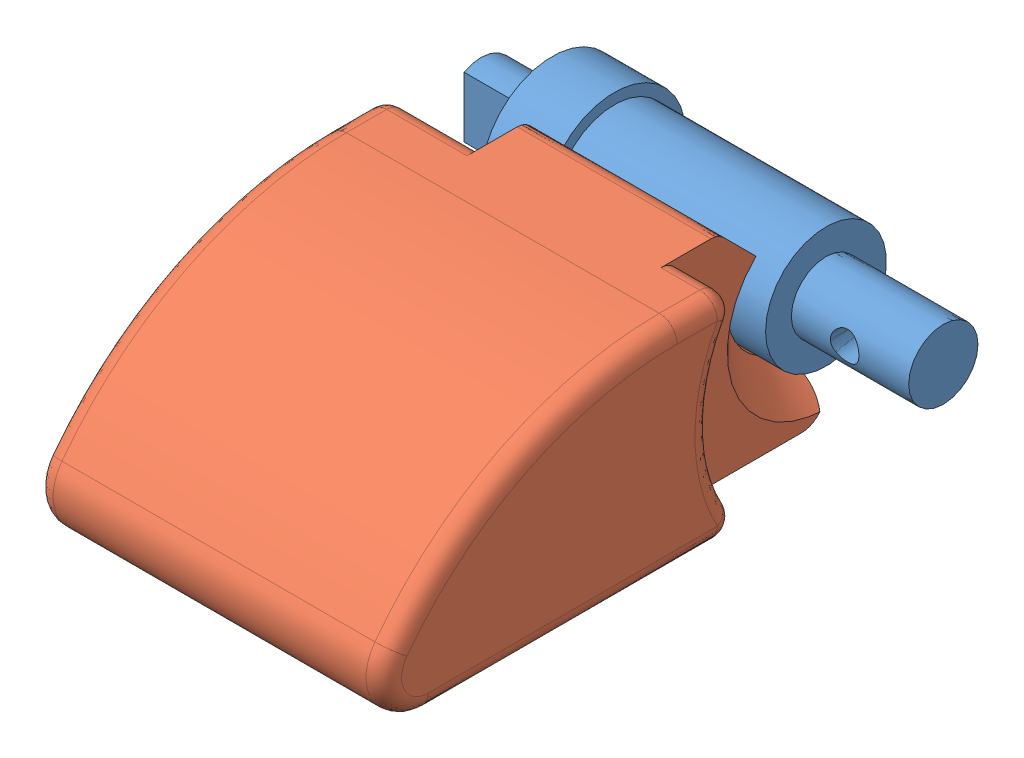
SolidWorks assembly finger tip with axil, configuration Default. Lengths in mm.
Overall size (26 12.05 32).
2 component instances, 2 part files, 3 mates.
Components (placement in the parent):
- axil-1: axil [Default] at (10.1326 12.5625 21.4703) size (26 8 8)
- motor mount tip-1: motor mount tip [Default] at (8.5826 12.5625 25.9703) x (-1 0 0) z (0 1 0) size (19.6 29.04 12.05)
Mates (geometry in assembly coordinates):
- Concentric4: concentric aligned: cylinder of axil-1 through (6.0826 12.5625 24.8703) axis (0 0 1) radius 0.8; cylinder of motor mount tip-1 through (6.0826 12.5625 20.9703) axis (0 0 1) radius 0.75
- Concentric5: concentric aligned: cylinder of axil-1 through (11.0826 12.5625 24.8703) axis (0 0 1) radius 0.8; cylinder of motor mount tip-1 through (11.0826 12.5625 20.9703) axis (0 0 1) radius 0.75
- Concentric6: concentric anti-aligned: cylinder of axil-1 through (10.1326 12.5625 21.4703) axis (-1 0 0) radius 3.4; cylinder of motor mount tip-1 through (-9.2335 12.5625 21.4703) axis (1 0 0) radius 3.5
